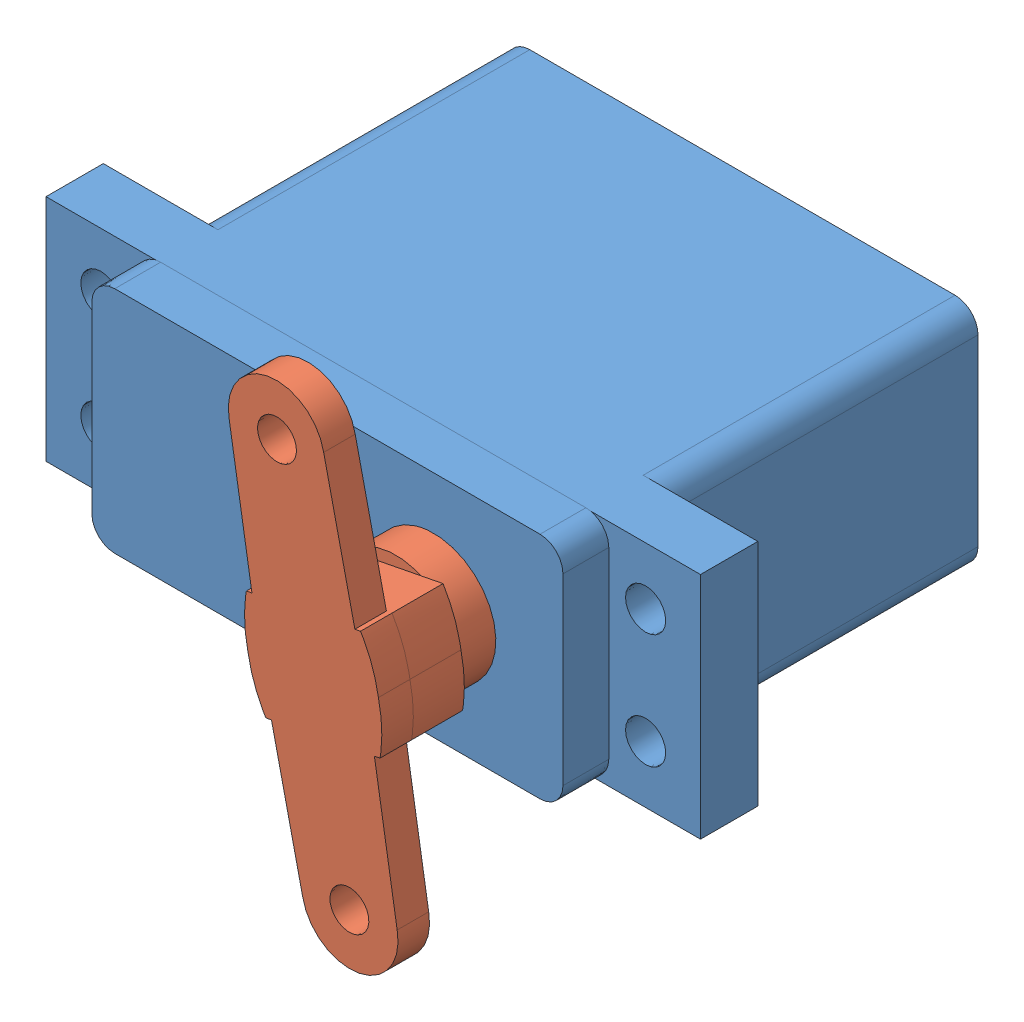
SolidWorks assembly CompleteServo, configuration Default. Lengths in mm.
Overall size (57.1 43.36 46.71).
2 component instances, 2 part files, 2 mates.
Components (placement in the parent):
- ServoBody-1: ServoBody [Default] at (-17.4659 25.4352 -8.0638) size (57.1 20.05 36.21)
- ServoDoor-1: ServoDoor [Default] at (18.5764 5.1235 38.6462) x (-0.191401 0.981512 0) z (0 0 -1) size (41.9 11.66 10.5)
Mates (geometry in assembly coordinates):
- Concentric3: concentric anti-aligned: circle of ServoDoor-1; circle of assembly
- Coincident5: coincident anti-aligned: plane of ServoBody-1 through (29.5805 2.1559 28.1462) normal (0 0 1); plane of ServoDoor-1 through (20.292 10.1559 28.1462) normal (0 0 -1)
